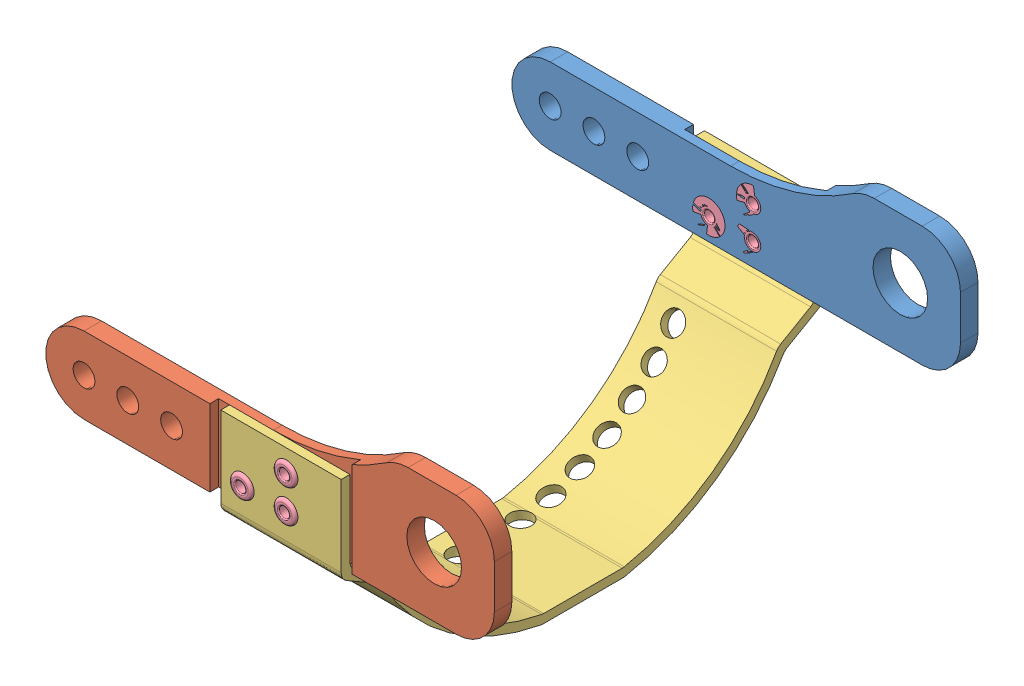
SolidWorks assembly joint_lower_assy3, configuration Default. Lengths in mm.
Overall size (82 49.4 89.4).
9 component instances, 4 part files, 19 mates.
Components (placement in the parent):
- joint_lower_right-1: joint_lower_right [Default] at origin size (82 22 3.2)
- joint_lower_left-2: joint_lower_left [Default] at (0 0 85.2) size (82 22 3.2)
- joint_lower_bridge3-1: joint_lower_bridge3 [Default] at (25 7 44.2) size (22 41.4 88.4)
- Заклепка головка потайная DIN 7337 B-1: Заклепка головка потайная DIN 7337 B [3x6-2,5] at (29 -3 85.2) x (0 0 1) z (-0.998692 -0.05113 0) size (3.7 6 6)
- Заклепка головка потайная DIN 7337 B-3: Заклепка головка потайная DIN 7337 B [3x6-2,5] at (37 -3 85.2) x (0 0 1) z (-0.977952 -0.208828 0) size (3.7 6 6)
- Заклепка головка потайная DIN 7337 B-5: Заклепка головка потайная DIN 7337 B [3x6-2,5] at (37 3 85.2) x (0 0 1) z (-0.943401 -0.331653 0) size (3.7 6 6)
- Заклепка головка потайная DIN 7337 B-7: Заклепка головка потайная DIN 7337 B [3x6-2,5] at (37 -3 3.2) x (0 0 -1) z (-0.90838 0.418146 0) size (3.7 6 6)
- Заклепка головка потайная DIN 7337 B-9: Заклепка головка потайная DIN 7337 B [3x6-2,5] at (29 -3 3.2) x (0 0 -1) z (0.88427 -0.466977 0) size (3.7 6 6)
- Заклепка головка потайная DIN 7337 B-11: Заклепка головка потайная DIN 7337 B [3x6-2,5] at (37 3 3.2) x (0 0 -1) z (-0.879685 0.475557 0) size (3.7 6 6)
Mates (geometry in assembly coordinates):
- Concentric1: concentric aligned: cylinder of joint_lower_right-1 through (64 4 -14.1421) axis (0 0 1) radius 5; cylinder of joint_lower_left-2 through (64 4 71.0579) axis (0 0 1) radius 5
- Parallel1: parallel aligned: plane of joint_lower_right-1 through (0 0 0) normal (0 1 0); plane of joint_lower_left-2 through (0 0 85.2) normal (0 1 0)
- Coincident1: coincident anti-aligned: plane of joint_lower_bridge3-1 through (47 -8 86.8) normal (0 0 -1); plane of joint_lower_left-2 through (0 0 86.8) normal (0 0 1)
- Coincident2: coincident aligned: plane of joint_lower_left-2 through (0 7 88.4) normal (0 1 0); plane of joint_lower_bridge3-1 through (47 7 88.4) normal (0 1 0)
- Coincident3: coincident anti-aligned: plane of joint_lower_bridge3-1 through (47 -8 1.6) normal (0 0 1); plane of joint_lower_right-1 through (0 0 1.6) normal (0 0 -1)
- Distance2: distance = 28 mm aligned: plane of joint_lower_left-2 through (75 0 88.4) normal (1 0 0); plane of joint_lower_bridge3-1 through (47 7 44.2) normal (1 0 0)
- Concentric2: concentric anti-aligned: circle of Заклепка головка потайная DIN 7337 B-1; cylinder of joint_lower_left-2 through (29 -3 86.8) axis (0 0 1) radius 1.5
- Coincident4: coincident aligned: plane of joint_lower_left-2 through (68 0 85.2) normal (0 0 -1); plane of Заклепка головка потайная DIN 7337 B-1 through (29.059 -4.153 85.2) normal (0 0 -1)
- Concentric3: concentric anti-aligned: circle of Заклепка головка потайная DIN 7337 B-3; cylinder of joint_lower_left-2 through (37 -3 86.8) axis (0 0 1) radius 1.5
- Coincident5: coincident aligned: plane of joint_lower_left-2 through (68 0 85.2) normal (0 0 -1); plane of Заклепка головка потайная DIN 7337 B-3 through (37.2411 -4.129 85.2) normal (0 0 -1)
- Concentric4: concentric anti-aligned: circle of Заклепка головка потайная DIN 7337 B-5; cylinder of joint_lower_left-2 through (37 3 86.8) axis (0 0 1) radius 1.5
- Coincident6: coincident aligned: plane of joint_lower_left-2 through (68 0 85.2) normal (0 0 -1); plane of Заклепка головка потайная DIN 7337 B-5 through (37.3829 1.9109 85.2) normal (0 0 -1)
- Concentric5: concentric anti-aligned: circle of Заклепка головка потайная DIN 7337 B-7; cylinder of joint_lower_right-1 through (37 -3 1.6) axis (0 0 -1) radius 1.5
- Coincident7: coincident aligned: plane of joint_lower_right-1 through (68 0 3.2) normal (0 0 1); plane of Заклепка головка потайная DIN 7337 B-7 through (37.4827 -1.9513 3.2) normal (0 0 1)
- Concentric6: concentric anti-aligned: circle of Заклепка головка потайная DIN 7337 B-9; cylinder of joint_lower_right-1 through (29 -3 1.6) axis (0 0 -1) radius 1.5
- Coincident8: coincident aligned: plane of joint_lower_right-1 through (68 0 3.2) normal (0 0 1); plane of Заклепка головка потайная DIN 7337 B-9 through (28.4609 -4.0209 3.2) normal (0 0 1)
- Concentric7: concentric anti-aligned: circle of Заклепка головка потайная DIN 7337 B-11; cylinder of joint_lower_right-1 through (37 3 1.6) axis (0 0 -1) radius 1.5
- Coincident9: coincident aligned: plane of joint_lower_right-1 through (68 0 3.2) normal (0 0 1); plane of Заклепка головка потайная DIN 7337 B-11 through (37.549 4.0156 3.2) normal (0 0 1)
- Concentric8: concentric anti-aligned: cylinder of joint_lower_left-2 through (29 -3 86.8) axis (0 0 1) radius 1.5; cylinder of Заклепка головка потайная DIN 7337 B-1 through (29 -3 85.2) axis (0 0 -1) radius 1.5
